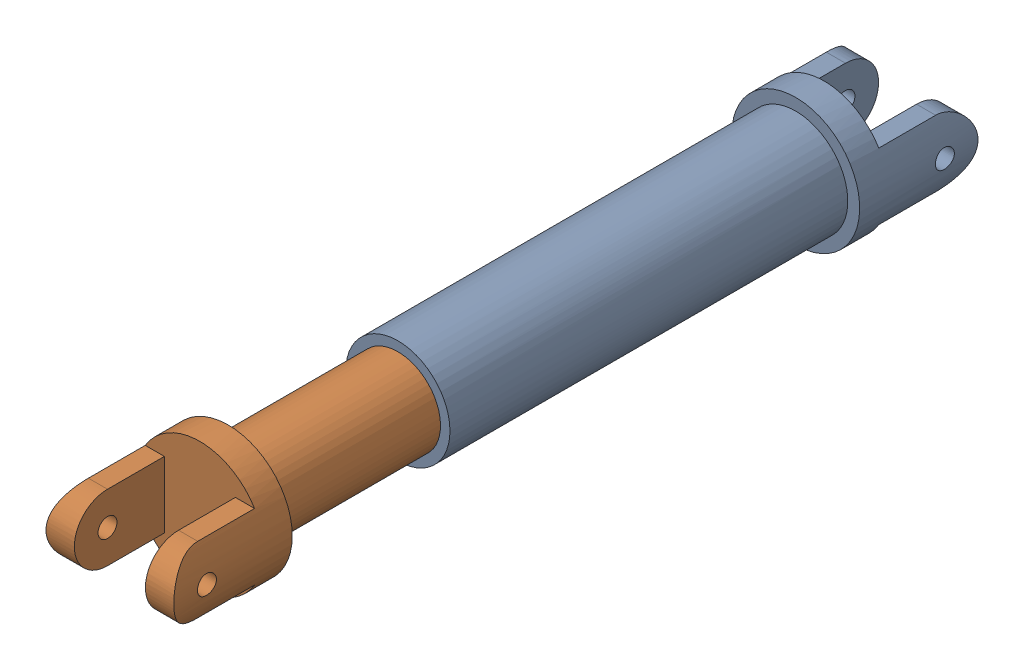
SolidWorks assembly Slip Yoke_fore, configuration Default. Lengths in mm.
2 component instances, 2 part files, 3 mates.
Components (placement in the parent):
- U Joint A - Outer Yoke_Rear-1: U Joint A - Outer Yoke_Rear [Default] at (19.5991 29.2682 47.9142) size (13.5 13.5 54.5)
- U Joint B - Inner Yoke_Rear-1: U Joint B - Inner Yoke_Rear [Default] at (19.5991 29.2682 63.8158) x (-1 0 0) z (0 0 -1) size (13.5 13.5 58.5)
Mates (geometry in assembly coordinates):
- Concentric1: concentric: cylinder of U Joint A - Outer Yoke_Rear-1 through (19.5991 29.2682 26.9142) axis (0 0 1) radius 4.5; cylinder of U Joint B - Inner Yoke_Rear-1 through (19.5991 29.2682 27.6549) axis (0 0 1) radius 4.5
- Coincident2: coincident: plane of U Joint A - Outer Yoke_Rear-1 through (20.0991 25.2961 26.9142) normal (0 1 0); plane of U Joint B - Inner Yoke_Rear-1 through (20.0991 25.2961 73.6549) normal (0 -1 0)
- LimitDistance2: limit distance = 0.7407 mm: plane of U Joint A - Outer Yoke_Rear-1 through (19.5991 29.2682 26.9142) normal (0 0 1); plane of U Joint B - Inner Yoke_Rear-1 through (19.5991 29.2682 27.6549) normal (0 0 -1)
